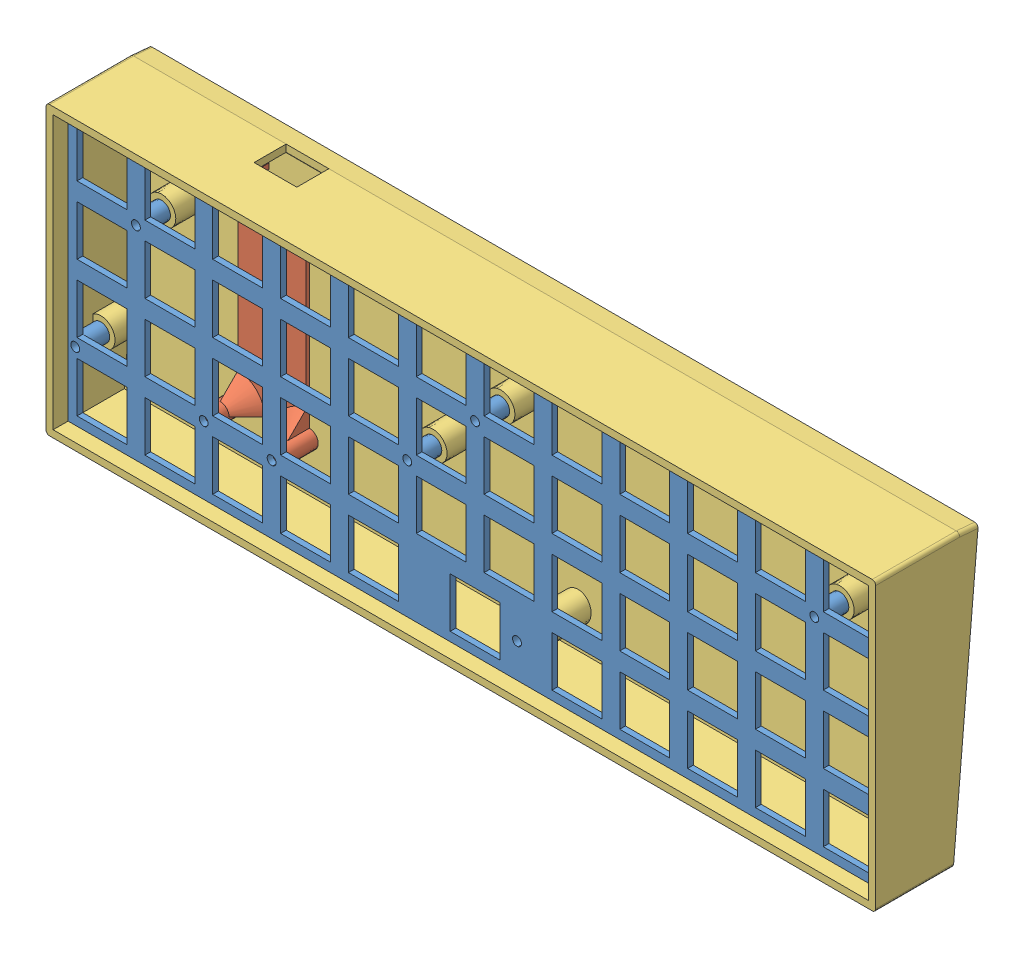
SolidWorks assembly Keyboard, configuration Predeterminado. Lengths in mm.
Overall size (233 84.54 35.81).
3 component instances, 3 part files, 7 mates.
Components (placement in the parent):
- 01-Plate-1: 01-Plate [Predeterminado] at origin size (228.6 76.2 7.2)
- 02-TeensyBase-1: 02-TeensyBase [Predeterminado] at (47.625 28.575 -8) x (-1 0 0) z (0 0 -1) size (24.05 59.65 13.25)
- 03-Body-1: 03-Body [Predeterminado] at (-2.2 -4.0926 -16.0322) x (0 0.996195 -0.087156) z (1 0 0) size (82.35 28.74 233)
Mates (geometry in assembly coordinates):
- Coincidente1: coordinate: point of 01-Plate-1
- Coincidente2: coincident anti-aligned: plane of 01-Plate-1 through (0 0 0) normal (0 0 -1); plane of 02-TeensyBase-1 through (38.1 19.05 0) normal (0 0 1)
- Concéntrica1: concentric aligned: cylinder of 01-Plate-1 through (38.1 19.05 -5.6) axis (0 0 1) radius 1.25; cylinder of 02-TeensyBase-1 through (38.1 19.05 -4) axis (0 0 1) radius 1.7
- Concéntrica2: concentric aligned: cylinder of 01-Plate-1 through (57.15 74.2 -5.6) axis (0 0 1) radius 1.25; cylinder of 02-TeensyBase-1 through (57.15 74.2 -4) axis (0 0 1) radius 1.7
- Ancho1: width anti-aligned: plane of 01-Plate-1 through (0 0 1.6) normal (-1 0 0); plane of 03-Body-1 through (228.6 0 1.6) normal (1 0 0); plane of 01-Plate-1 through (-0.2 -4.0926 -16.0322) normal (1 0 0); plane of 03-Body-1 through (228.8 -4.0926 -16.0322) normal (-1 0 0)
- Ancho2: width anti-aligned: plane of 02-TeensyBase-1 through (57.15 76.2 -9) normal (0 1 0); plane of 03-Body-1 through (0 0 1.6) normal (0 -1 0); plane of 01-Plate-1 through (230.8 76.4 -18) normal (0 -1 0); plane of 03-Body-1 through (230.8 -0.2 5.6) normal (0 1 0)
- Coincidente3: coincident anti-aligned: plane of 01-Plate-1 through (2 19.05 -5.6) normal (0 0 -1); plane of 03-Body-1 through (2 19.05 -5.6) normal (0 0 1)
